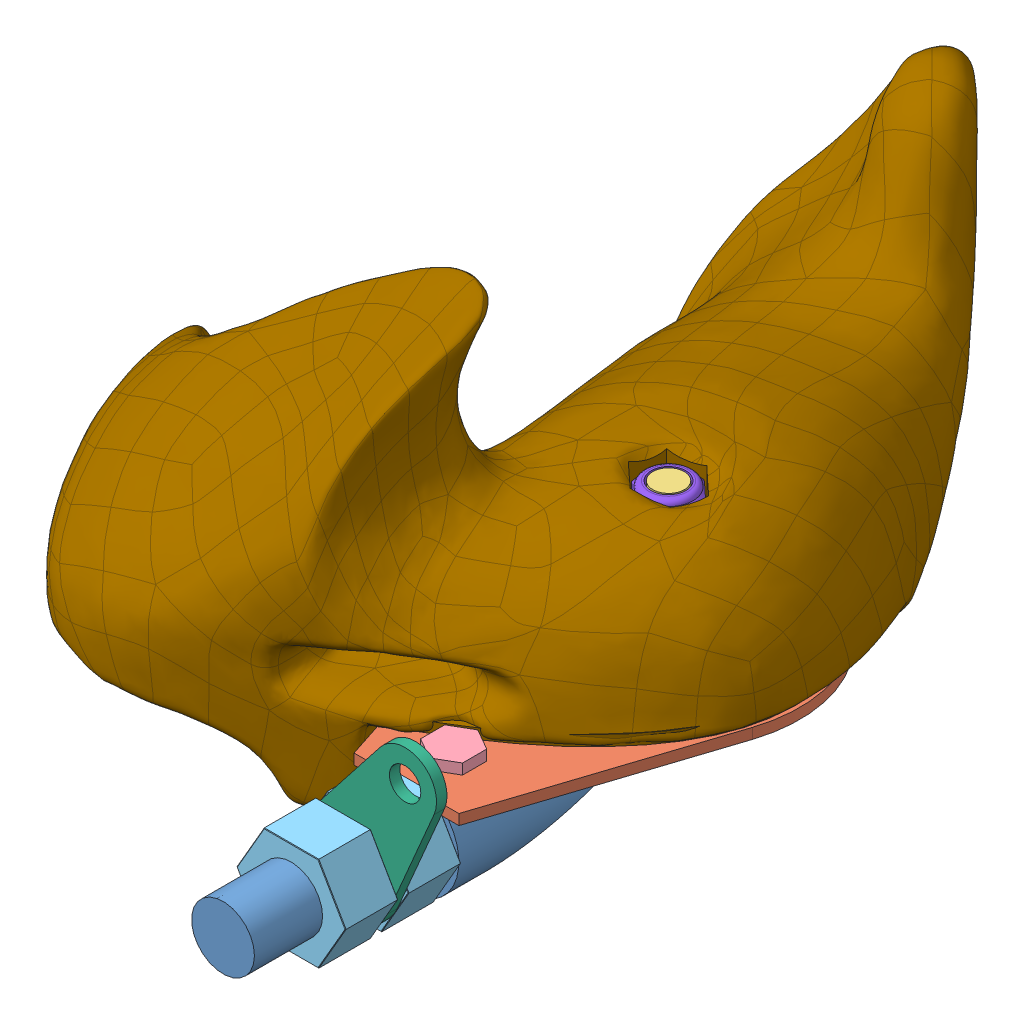
SolidWorks assembly rr-001-000-001-rucni-rizeni, configuration Výchozí. Lengths in mm.
Overall size (148.68 74.56 181.49).
10 component instances, 9 part files, 18 mates.
Components (placement in the parent):
- rr-001-001-002-nadstavec-sroub-2: rr-001-001-002-nadstavec-sroub [Výchozí] at origin size (20 16 75)
- rr-001-002-002-nadstavec-plocha-1: rr-001-002-002-nadstavec-plocha [Výchozí] at (0 6 -10) x (-1 0 0) z (0 1 0) size (50 75 2)
- rr-001-003-002-sroub-rucka-1: rr-001-003-002-sroub-rucka [Výchozí] at (0 33 -10) x (1 0 0) z (0 -1 0) size (10 11.55 31)
- rr-001-004-002-sroub-nadstavec-1: rr-001-004-002-sroub-nadstavec [Výchozí] at (0 -4 31) x (1 0 0) z (0 1 0) size (8 9.24 14)
- rr-001-005-001-matice-m10-1: rr-001-005-001-matice-m10 [Výchozí] at (0 0 50) x (-0.866025 -0.5 0) z (0 0 -1) size (18 20.78 10)
- rr-001-005-001-matice-m10-2: rr-001-005-001-matice-m10 [Výchozí] at (0 0 52) x (0.866025 -0.5 0) z (0 0 1) size (18 20.78 10)
- rr-001-006-002-nadstavec-lanko-1: rr-001-006-002-nadstavec-lanko [Výchozí] at (0 0 50) x (0.860073 -0.510171 0) z (0 0 1) size (18 38 2)
- rr-001-007-002-podlozka-1: rr-001-007-002-podlozka [Výchozí] at (0 6 -10) x (1 0 0) z (0 -1 0) size (10 10 1)
- rr-001-008-002-m6-1: rr-001-008-002-m6 [Default] at (0 33 -10) x (0.678396 0 -0.734696) z (0 -1 0) size (9.8 12.45 6)
- rr-001-010-002-rukojet-1: rr-001-010-002-rukojet [Výchozí] at (0 8 -10) x (0.297068 0 0.954856) z (0 -1 0) size (135.79 113.47 68.96)
Mates (geometry in assembly coordinates):
- Sjednocená2: coincident anti-aligned: line of rr-001-001-002-nadstavec-sroub-2 through (8 6 40) axis (-1 0 0); line of rr-001-002-002-nadstavec-plocha-1 through (-10 6 40) axis (1 0 0)
- Soustředná1: concentric aligned: circle of rr-001-001-002-nadstavec-sroub-2; circle of rr-001-002-002-nadstavec-plocha-1
- Sjednocená3: coincident anti-aligned: circle of rr-001-002-002-nadstavec-plocha-1; circle of rr-001-007-002-podlozka-1
- Sjednocená4: coincident aligned: circle of rr-001-003-002-sroub-rucka-1; circle of rr-001-007-002-podlozka-1
- Soustředná2: concentric aligned: circle of rr-001-002-002-nadstavec-plocha-1; circle of rr-001-010-002-rukojet-1
- Sjednocená5: coincident anti-aligned: plane of rr-001-002-002-nadstavec-plocha-1 through (0 8 -10) normal (0 1 0); plane of rr-001-010-002-rukojet-1 through (0 8 -10) normal (0 -1 0)
- Soustředná3: concentric aligned: circle of rr-001-001-002-nadstavec-sroub-2; circle of rr-001-005-001-matice-m10-1
- Sjednocená6: coincident anti-aligned: plane of rr-001-001-002-nadstavec-sroub-2 through (0 0 40) normal (0 0 1); plane of rr-001-005-001-matice-m10-1 through (0 0 40) normal (0 0 -1)
- Soustředná4: concentric aligned: cylinder of rr-001-001-002-nadstavec-sroub-2 through (0 0 40) axis (0 0 1) radius 6; cylinder of rr-001-006-002-nadstavec-lanko-1 through (0 0 33.0294) axis (0 0 1) radius 6
- Sjednocená7: coincident anti-aligned: plane of rr-001-005-001-matice-m10-1 through (0 0 50) normal (0 0 1); plane of rr-001-006-002-nadstavec-lanko-1 through (0 0 50) normal (0 0 -1)
- Soustředná5: concentric anti-aligned: cylinder of rr-001-001-002-nadstavec-sroub-2 through (0 0 40) axis (0 0 1) radius 6; cylinder of rr-001-005-001-matice-m10-2 through (0 0 52) axis (0 0 -1) radius 5.1
- Sjednocená8: coincident anti-aligned: plane of rr-001-005-001-matice-m10-2 through (0 0 52) normal (0 0 -1); plane of rr-001-006-002-nadstavec-lanko-1 through (0 0 52) normal (0 0 1)
- Soustředná6: concentric anti-aligned: cylinder of rr-001-003-002-sroub-rucka-1 through (0 5 -10) axis (0 1 0) radius 3; cylinder of rr-001-008-002-m6-1 through (0 27 -10) axis (0 -1 0) radius 3.3
- Sjednocená9: coincident anti-aligned: plane of rr-001-008-002-m6-1 through (1.2457 27 -15.5192) normal (0 -1 0); plane of rr-001-010-002-rukojet-1 through (0 27 -10) normal (0 1 0)
- Sjednocená10: coincident aligned: circle of rr-001-002-002-nadstavec-plocha-1; circle of rr-001-004-002-sroub-nadstavec-1
- Rovnoběžná1: parallel aligned: plane of rr-001-005-001-matice-m10-1 through (5.1962 9 40) normal (0.866025 0.5 0); plane of rr-001-005-001-matice-m10-2 through (10.3923 0 62) normal (0.866025 0.5 0)
- Rovnoběžná2: parallel aligned: plane of rr-001-002-002-nadstavec-plocha-1 through (0 8 -10) normal (0 1 0); plane of rr-001-005-001-matice-m10-1 through (-5.1962 9 40) normal (0 1 0)
- Rovnoběžná3: parallel aligned: plane of rr-001-008-002-m6-1 through (-5.4026 27 -8.3192) normal (-0.975464 0 -0.22016); plane of rr-001-010-002-rukojet-1 through (5.8436 61.0559 -11.818) normal (-0.975464 0 -0.22016)
